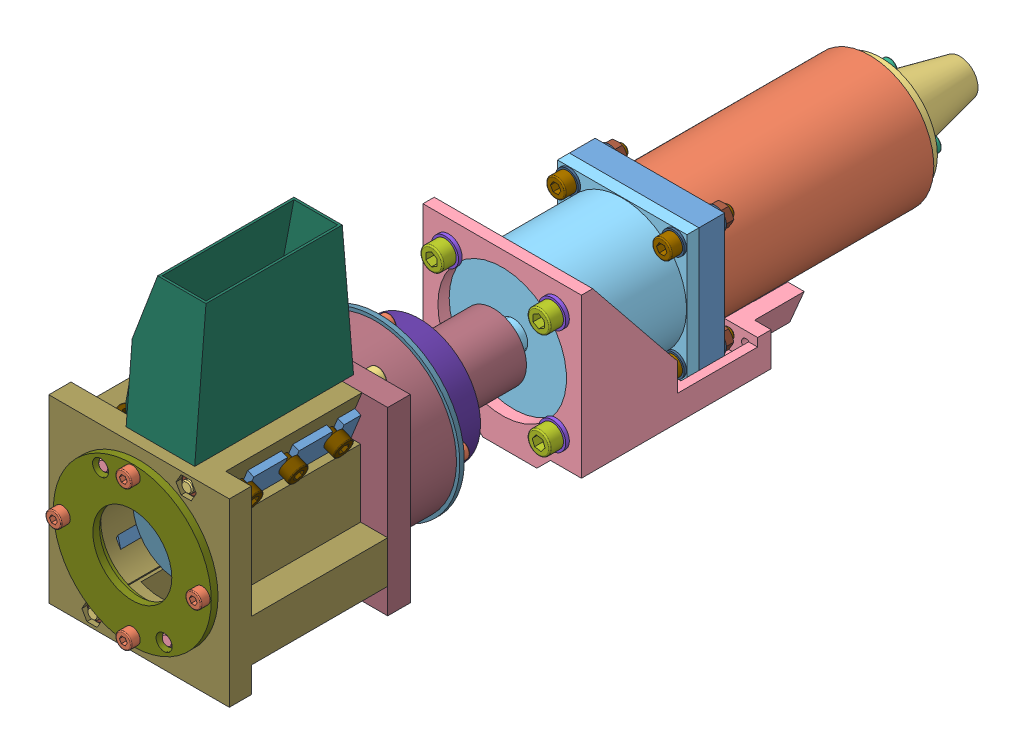
SolidWorks assembly 01_00_00-shredder_unit, configuration Standard. Lengths in mm.
Overall size (95.07 144 370.86).
107 component instances, 40 part files, 5 mates.
Components (placement in the parent):
- 01_01_00-powertrain_unit-1: 01_01_00-powertrain_unit [Standard] at (17.1226 7.6648 222.9) size (70.23 76.3 222.9)
  - 01_01_01-adapterplate_planetary_gear-1: 01_01_01-adapterplate_planetary_gear [Standard] at (50.4757 14.9234 40.5237) size (57.4 57.4 11.4)
  - 01_01_02-engine-1: 01_01_02-engine [Standard] at (50.4757 14.9234 -52.4763) size (56.8 56.8 93)
  - 01_01_03-engine_end_cap-1: 01_01_03-engine_end_cap [Standard] at (50.4757 14.9234 -52.4763) x (0 0 -1) z (1 0 0) size (40 50 50)
  - 01_01_04-engine_mount-1: 01_01_04-engine_mount [Standard] at (50.4757 14.9234 105.4237) x (-1 0 0) z (0 0 -1) size (70.23 76.3 106.1)
  - 01_01_05-planetary_gear-1: 01_01_05-planetary_gear [Standard] at (50.4757 14.9234 57.2237) size (57.4 57.4 78.5)
  - 01_01_06-cylinder_screw_M4x10-DIN912-1: 01_01_06-cylinder_screw_M4x10-DIN912 [Default] at (50.4757 34.3634 -57.4763) x (-0.923728 -0.383049 0) z (0 0 -1) size (7 7 14)
  - 01_01_06-cylinder_screw_M4x10-DIN912-2: 01_01_06-cylinder_screw_M4x10-DIN912 [Default] at (31.0357 14.9234 -57.4763) x (-0.923728 -0.383049 0) z (0 0 -1) size (7 7 14)
  - 01_01_06-cylinder_screw_M4x10-DIN912-3: 01_01_06-cylinder_screw_M4x10-DIN912 [Default] at (50.4757 -4.5166 -57.4763) x (-0.923728 -0.383049 0) z (0 0 -1) size (7 7 14)
  - 01_01_06-cylinder_screw_M4x10-DIN912-4: 01_01_06-cylinder_screw_M4x10-DIN912 [Default] at (69.9157 14.9234 -57.4763) x (-0.923728 -0.383049 0) z (0 0 -1) size (7 7 14)
  - 01_01_07-cylinder_screw_M6x16-DIN912-1: 01_01_07-cylinder_screw_M6x16-DIN912 [Default] at (74.2282 38.3194 112.0237) x (0.873403 -0.486997 0) z (0 0 1) size (10 10 22)
  - 01_01_07-cylinder_screw_M6x16-DIN912-2: 01_01_07-cylinder_screw_M6x16-DIN912 [Default] at (26.7231 38.3194 112.0237) x (0.863476 -0.50439 0) z (0 0 1) size (10 10 22)
  - 01_01_07-cylinder_screw_M6x16-DIN912-3: 01_01_07-cylinder_screw_M6x16-DIN912 [Default] at (26.7231 -8.4726 112.0237) x (0.985082 0.172086 0) z (0 0 1) size (10 10 22)
  - 01_01_07-cylinder_screw_M6x16-DIN912-4: 01_01_07-cylinder_screw_M6x16-DIN912 [Default] at (74.2282 -8.4726 112.0237) x (0.989059 -0.147523 0) z (0 0 1) size (10 10 22)
  - 01_01_08-washer_M6-ISO7089-1: 01_01_08-washer_M6-ISO7089 [Default] at (26.7231 38.3194 110.4237) size (12 12 1.6)
  - 01_01_08-washer_M6-ISO7089-2: 01_01_08-washer_M6-ISO7089 [Default] at (74.2282 38.3194 110.4237) size (12 12 1.6)
  - 01_01_08-washer_M6-ISO7089-3: 01_01_08-washer_M6-ISO7089 [Default] at (26.7231 -8.4726 112.0237) x (-0.923728 -0.383049 0) z (0 0 -1) size (12 12 1.6)
  - 01_01_08-washer_M6-ISO7089-4: 01_01_08-washer_M6-ISO7089 [Default] at (74.2282 -8.4726 110.4237) size (12 12 1.6)
  - 01_01_09-cylinder_screw_M5x25-DIN912-1: 01_01_09-cylinder_screw_M5x25-DIN912 [Default] at (73.9757 -8.5766 58.2237) size (8.5 8.5 30)
  - 01_01_09-cylinder_screw_M5x25-DIN912-2: 01_01_09-cylinder_screw_M5x25-DIN912 [Default] at (26.9757 -8.5766 58.2237) size (8.5 8.5 30)
  - 01_01_09-cylinder_screw_M5x25-DIN912-3: 01_01_09-cylinder_screw_M5x25-DIN912 [Default] at (73.9757 38.4234 58.2237) size (8.5 8.5 30)
  - 01_01_09-cylinder_screw_M5x25-DIN912-4: 01_01_09-cylinder_screw_M5x25-DIN912 [Default] at (26.9757 38.4234 58.2237) size (8.5 8.5 30)
  - 01_01_10-washer_M5-ISO7089-1: 01_01_10-washer_M5-ISO7089 [Default] at (73.9757 38.4234 57.2237) size (10 10 1)
  - 01_01_10-washer_M5-ISO7089-2: 01_01_10-washer_M5-ISO7089 [Default] at (26.9757 38.4234 57.2237) size (10 10 1)
  - 01_01_10-washer_M5-ISO7089-3: 01_01_10-washer_M5-ISO7089 [Default] at (73.9757 -8.5766 39.5237) size (10 10 1)
  - 01_01_10-washer_M5-ISO7089-4: 01_01_10-washer_M5-ISO7089 [Default] at (73.9757 38.4234 39.5237) size (10 10 1)
  - 01_01_10-washer_M5-ISO7089-5: 01_01_10-washer_M5-ISO7089 [Default] at (26.9757 -8.5766 57.2237) size (10 10 1)
  - 01_01_10-washer_M5-ISO7089-6: 01_01_10-washer_M5-ISO7089 [Default] at (73.9757 -8.5766 57.2237) size (10 10 1)
  - 01_01_10-washer_M5-ISO7089-7: 01_01_10-washer_M5-ISO7089 [Default] at (26.9757 38.4234 39.5237) size (10 10 1)
  - 01_01_10-washer_M5-ISO7089-8: 01_01_10-washer_M5-ISO7089 [Default] at (26.9757 -8.5766 39.5237) size (10 10 1)
  - 01_02_17-nut_M5-DIN934-1: 01_02_17-nut_M5-DIN934 [Default] at (26.9757 -8.5766 35.5237) size (9.24 8 4)
  - 01_02_17-nut_M5-DIN934-2: 01_02_17-nut_M5-DIN934 [Default] at (26.9757 38.4234 35.5237) size (9.24 8 4)
  - 01_02_17-nut_M5-DIN934-3: 01_02_17-nut_M5-DIN934 [Default] at (73.9757 -8.5766 35.5237) size (9.24 8 4)
  - 01_02_17-nut_M5-DIN934-4: 01_02_17-nut_M5-DIN934 [Default] at (73.9757 38.4234 35.5237) size (9.24 8 4)
- 01_02_00-cutting_unit-1: 01_02_00-cutting_unit [Standard] at (-26.7271 2.1966 389.5832) size (95.07 144 164.2)
  - 01_02_01-block-2: 01_02_01-block [Standard] at (54.3254 -19.6084 24.6959) size (81 88 109)
  - 01_02_02-counterplate-2: 01_02_02-counterplate [Standard] at (94.3254 20.3916 34.4959) x (0 1 0) z (0 0 -1) size (87.48 95.07 35)
  - 01_02_03-milling_Cutter-2: 01_02_03-milling_Cutter [Standard] at (94.3254 20.3916 87.4959) x (0 0 -1) z (0.834594 0.550866 0) size (115 40 40)
  - 01_02_04-hopper-3: 01_02_04-hopper [Standard] at (90.1822 35.5166 34.4959) size (35.4 73 70.4)
  - 01_02_05-deep_groove_ball_bearing_FAG6005_2Z-DIN625-1-3: 01_02_05-deep_groove_ball_bearing_FAG6005_2Z-DIN625-1 [Default] at (94.3254 20.3916 1.9959) x (0 0 1) z (0.97178 0.235887 0) size (12 47 47)
    - deep groove ball bearing _01-1: deep groove ball bearing _01 [Default] at origin size (12 32 32)
    - deep groove ball bearing _02-1: deep groove ball bearing _02 [Default] at origin size (12 47 47)
    - deep groove ball bearing _03-1: deep groove ball bearing _03 [Default] at origin size (8.55 8.62 8.66)
    - deep groove ball bearing _04-1: deep groove ball bearing _04 [Default] at origin size (8.18 8.8 8.53)
    - deep groove ball bearing _05-1: deep groove ball bearing _05 [Default] at origin size (8.18 8.8 8.53)
    - deep groove ball bearing _06-1: deep groove ball bearing _06 [Default] at origin size (8.18 8.8 8.53)
    - deep groove ball bearing _07-1: deep groove ball bearing _07 [Default] at origin size (8.6 8.66 8.93)
    - deep groove ball bearing _08-1: deep groove ball bearing _08 [Default] at origin size (8.6 8.66 8.93)
    - deep groove ball bearing _09-1: deep groove ball bearing _09 [Default] at origin size (8.51 7.97 8.51)
    - deep groove ball bearing _10-1: deep groove ball bearing _10 [Default] at origin size (8.51 7.97 8.51)
    - deep groove ball bearing _11-1: deep groove ball bearing _11 [Default] at origin size (8.51 7.97 8.51)
    - deep groove ball bearing _12-1: deep groove ball bearing _12 [Default] at origin size (7.71 8.16 8.45)
    - deep groove ball bearing _13-1: deep groove ball bearing _13 [Default] at origin size (1.7 43.25 43.25)
    - deep groove ball bearing _14-1: deep groove ball bearing _14 [Default] at origin size (1.7 43.25 43.25)
  - 01_02_05-deep_groove_ball_bearing_FAG6005_2Z-DIN625-1-4: 01_02_05-deep_groove_ball_bearing_FAG6005_2Z-DIN625-1 [Default] at (94.3254 20.3916 30.4959) x (0 0 -1) z (0.022494 -0.999747 0) size (12 47 47)
    - deep groove ball bearing _01-1: deep groove ball bearing _01 [Default] at origin size (12 32 32)
    - deep groove ball bearing _02-1: deep groove ball bearing _02 [Default] at origin size (12 47 47)
    - deep groove ball bearing _03-1: deep groove ball bearing _03 [Default] at origin size (8.55 8.62 8.66)
    - deep groove ball bearing _04-1: deep groove ball bearing _04 [Default] at origin size (8.18 8.8 8.53)
    - deep groove ball bearing _05-1: deep groove ball bearing _05 [Default] at origin size (8.18 8.8 8.53)
    - deep groove ball bearing _06-1: deep groove ball bearing _06 [Default] at origin size (8.18 8.8 8.53)
    - deep groove ball bearing _07-1: deep groove ball bearing _07 [Default] at origin size (8.6 8.66 8.93)
    - deep groove ball bearing _08-1: deep groove ball bearing _08 [Default] at origin size (8.6 8.66 8.93)
    - deep groove ball bearing _09-1: deep groove ball bearing _09 [Default] at origin size (8.51 7.97 8.51)
    - deep groove ball bearing _10-1: deep groove ball bearing _10 [Default] at origin size (8.51 7.97 8.51)
    - deep groove ball bearing _11-1: deep groove ball bearing _11 [Default] at origin size (8.51 7.97 8.51)
    - deep groove ball bearing _12-1: deep groove ball bearing _12 [Default] at origin size (7.71 8.16 8.45)
    - deep groove ball bearing _13-1: deep groove ball bearing _13 [Default] at origin size (1.7 43.25 43.25)
    - deep groove ball bearing _14-1: deep groove ball bearing _14 [Default] at origin size (1.7 43.25 43.25)
  - 01_02_06-bearing_Ring-1: 01_02_06-bearing_Ring [Standard] at (94.3254 20.3916 30.4959) x (0.18936 -0.981908 0) z (0 0 1) size (30 30 2)
  - 01_02_07-sleeve_milling_cutter_gear-2: 01_02_07-sleeve_milling_cutter_gear [Standard] at (94.3254 20.3916 -52.5041) size (29 29 50)
  - 01_02_08-bearing_sleeve_1-2: 01_02_08-bearing_sleeve_1 [Standard] at (94.3254 20.3916 -2.0041) x (0 0 1) z (-1 0 0) size (4 75 75)
  - 01_02_09-bearing_sleeve_2-2: 01_02_09-bearing_sleeve_2 [Standard] at (94.3254 20.3916 16.4959) x (0 0 1) z (-0.620419 -0.784271 0) size (4.5 32 32)
  - 01_02_10-shredder_end_cap-1: 01_02_10-shredder_end_cap [Standard] at (94.3254 20.3916 107.6959) x (-1 0 0) z (0 0 -1) size (70 70 6)
  - 01_02_11-clamping_flange-1: 01_02_11-clamping_flange [Standard] at (94.3254 20.3916 -19.6381) x (0.999731 0.023181 0) z (0 0 1) size (54 54 15)
  - 01_02_12-cylinder_screw_M5x10-DIN912-1: 01_02_12-cylinder_screw_M5x10-DIN912 [Default] at (68.0038 -5.8815 64.6959) x (0.927184 -0.374607 0) z (0 0 1) size (14.82 8.28 8.28)
  - 01_02_12-cylinder_screw_M5x10-DIN912-2: 01_02_12-cylinder_screw_M5x10-DIN912 [Default] at (68.0523 46.7131 44.6959) x (-0.374607 -0.927184 0) z (0 0 1) size (14.82 8.28 8.28)
  - 01_02_12-cylinder_screw_M5x10-DIN912-3: 01_02_12-cylinder_screw_M5x10-DIN912 [Default] at (68.0038 -5.8815 44.6959) x (0.927184 -0.374607 0) z (0 0 1) size (14.82 8.28 8.28)
  - 01_02_12-cylinder_screw_M5x10-DIN912-4: 01_02_12-cylinder_screw_M5x10-DIN912 [Default] at (68.0523 46.7131 64.6959) x (-0.374607 -0.927184 0) z (0 0 1) size (14.82 8.28 8.28)
  - 01_02_12-cylinder_screw_M5x10-DIN912-5: 01_02_12-cylinder_screw_M5x10-DIN912 [Default] at (68.0523 46.7131 84.6959) x (-0.374607 -0.927184 0) z (-0.577142 0.233181 0.782645) size (14.82 8.28 8.28)
  - 01_02_12-cylinder_screw_M5x10-DIN912-6: 01_02_12-cylinder_screw_M5x10-DIN912 [Default] at (68.0038 -5.8815 84.6959) x (0.927184 -0.374607 0) z (0 0 1) size (14.82 8.28 8.28)
  - 01_02_12-cylinder_screw_M5x10-DIN912-7: 01_02_12-cylinder_screw_M5x10-DIN912 [Default] at (120.647 46.6646 84.6959) x (-0.927184 0.374607 0) z (0 0 1) size (14.82 8.28 8.28)
  - 01_02_12-cylinder_screw_M5x10-DIN912-8: 01_02_12-cylinder_screw_M5x10-DIN912 [Default] at (120.647 46.6646 64.6959) x (-0.927184 0.374607 0) z (0 0 1) size (14.82 8.28 8.28)
  - 01_02_12-cylinder_screw_M5x10-DIN912-9: 01_02_12-cylinder_screw_M5x10-DIN912 [Default] at (120.647 46.6646 44.6959) x (-0.927184 0.374607 0) z (-0.253198 -0.626687 -0.73699) size (14.82 8.28 8.28)
  - 01_02_12-cylinder_screw_M5x10-DIN912-10: 01_02_12-cylinder_screw_M5x10-DIN912 [Default] at (120.5984 -5.93 84.6959) x (0.374607 0.927184 0) z (0 0 1) size (14.82 8.28 8.28)
  - 01_02_12-cylinder_screw_M5x10-DIN912-11: 01_02_12-cylinder_screw_M5x10-DIN912 [Default] at (120.5984 -5.93 64.6959) x (0.374607 0.927184 0) z (0 0 1) size (14.82 8.28 8.28)
  - 01_02_12-cylinder_screw_M5x10-DIN912-12: 01_02_12-cylinder_screw_M5x10-DIN912 [Default] at (120.5984 -5.93 44.6959) x (0.374607 0.927184 0) z (0 0 1) size (14.82 8.28 8.28)
  - 01_02_13-Cutter_head-1: 01_02_13-Cutter_head [Standard] at (113.3407 28.5809 34.6959) x (0.374607 0.927184 0) z (0 0 1) size (25 3 60)
  - 01_02_13-Cutter_head-2: 01_02_13-Cutter_head [Standard] at (102.5147 1.3763 34.6959) x (0.927184 -0.374607 0) z (0 0 1) size (25 3 60)
  - 01_02_13-Cutter_head-3: 01_02_13-Cutter_head [Standard] at (86.136 39.4069 35.0959) x (-0.927184 0.374607 0) z (0 0 1) size (25 3 60)
  - 01_02_13-Cutter_head-4: 01_02_13-Cutter_head [Standard] at (75.3101 12.2022 35.0959) x (-0.374607 -0.927184 0) z (0 0 1) size (25 3 60)
  - 01_02_14-cylinder_screw_M4x12-DIN912-1: 01_02_14-cylinder_screw_M4x12-DIN912 [Default] at (63.3254 20.3916 107.6959) size (7 7 16)
  - 01_02_14-cylinder_screw_M4x12-DIN912-2: 01_02_14-cylinder_screw_M4x12-DIN912 [Default] at (94.3254 -10.6084 107.6959) size (7 7 16)
  - 01_02_14-cylinder_screw_M4x12-DIN912-3: 01_02_14-cylinder_screw_M4x12-DIN912 [Default] at (94.3254 51.3916 107.6959) size (7 7 16)
  - 01_02_14-cylinder_screw_M4x12-DIN912-4: 01_02_14-cylinder_screw_M4x12-DIN912 [Default] at (125.3254 20.3916 107.6959) size (7 7 16)
  - 01_02_14-cylinder_screw_M4x12-DIN912-5: 01_02_14-cylinder_screw_M4x12-DIN912 [Default] at (126.8254 20.3916 -2.0041) x (-0.923728 -0.383049 0) z (0 0 -1) size (7 7 16)
  - 01_02_14-cylinder_screw_M4x12-DIN912-6: 01_02_14-cylinder_screw_M4x12-DIN912 [Default] at (94.3254 -12.1084 -2.0041) x (-0.923728 -0.383049 0) z (0 0 -1) size (7 7 16)
  - 01_02_14-cylinder_screw_M4x12-DIN912-7: 01_02_14-cylinder_screw_M4x12-DIN912 [Default] at (94.3254 52.8916 -2.0041) x (-0.923728 -0.383049 0) z (0 0 -1) size (7 7 16)
  - 01_02_14-cylinder_screw_M4x12-DIN912-8: 01_02_14-cylinder_screw_M4x12-DIN912 [Default] at (61.8254 20.3916 -2.0041) x (-0.923728 -0.383049 0) z (0 0 -1) size (7 7 16)
  - 01_02_15-cylinder_screw_M5x80-DIN912-1: 01_02_15-cylinder_screw_M5x80-DIN912 [Default] at (73.4663 -14.3237 24.4959) x (0 0 1) z (-1 0 0) size (84.82 8.28 8.28)
  - 01_02_15-cylinder_screw_M5x80-DIN912-2: 01_02_15-cylinder_screw_M5x80-DIN912 [Default] at (115.1844 55.1068 24.4959) x (0 0 1) z (-1 0 0) size (84.82 8.28 8.28)
  - 01_02_16-cylinder_screw_M5x100-DIN912-1: 01_02_16-cylinder_screw_M5x100-DIN912 [Default] at (80.2412 46.88 6.4959) x (0 0 1) z (-1 0 0) size (104.82 8.28 8.28)
  - 01_02_16-cylinder_screw_M5x100-DIN912-2: 01_02_16-cylinder_screw_M5x100-DIN912 [Default] at (108.4095 -6.0969 6.4959) x (0 0 1) z (-1 0 0) size (104.82 8.28 8.28)
  - 01_02_17-nut_M5-DIN934-1: 01_02_17-nut_M5-DIN934 [Default] at (73.4663 -14.3237 98.6959) x (0.499182 -0.866497 0) z (0 0 1) size (9.24 8 4)
  - 01_02_17-nut_M5-DIN934-2: 01_02_17-nut_M5-DIN934 [Default] at (108.4054 -6.0984 98.6959) x (0.819585 -0.572958 0) z (0 0 1) size (9.24 8 4)
  - 01_02_17-nut_M5-DIN934-3: 01_02_17-nut_M5-DIN934 [Default] at (80.2412 46.88 98.6959) x (0.233113 0.97245 0) z (0 0 1) size (9.24 8 4)
  - 01_02_17-nut_M5-DIN934-4: 01_02_17-nut_M5-DIN934 [Default] at (115.1844 55.1068 98.6959) x (0.773993 -0.633194 0) z (0 0 1) size (9.24 8 4)
Mates (geometry in assembly coordinates):
- Konzentrisch1: concentric aligned: cylinder of 01_01_00-powertrain_unit-1/01_01_05-planetary_gear-1 through (8.4397 9.1765 370.2) axis (0 0 -1) radius 6.33; cylinder of ? through (8.4397 9.1765 487.7) axis (0 0 -1) radius 12.5
- Abstand2: distance = 3 mm anti-aligned: plane of 01_01_00-powertrain_unit-1/01_01_05-planetary_gear-1 through (8.4397 9.1765 345.2) normal (0 0 1); plane of ? through (8.4397 9.1765 348.2) normal (0 0 -1)
- Konzentrisch2: concentric aligned: cylinder of 01_01_00-powertrain_unit-1/01_01_05-planetary_gear-1 through (67.5983 22.5881 353.3237) axis (0 0 -1) radius 6.33; cylinder of 01_02_00-cutting_unit-1/01_02_07-sleeve_milling_cutter_gear-2 through (67.5983 22.5881 337.0791) axis (0 0 -1) radius 6.25
- Deckungsgleich1: coincident aligned: plane of 01_01_00-powertrain_unit-1/01_01_05-planetary_gear-1 through (67.5983 22.5881 353.3237) normal (0 0 1); circle of 01_02_00-cutting_unit-1/01_02_07-sleeve_milling_cutter_gear-2
- Parallel1: parallel aligned: plane of 01_01_00-powertrain_unit-1/01_01_05-planetary_gear-1 through (38.8983 -6.1119 328.3237) normal (0 -1 0); plane of 01_02_00-cutting_unit-1/01_02_02-counterplate-2 through (27.5983 -17.4119 414.0791) normal (0 -1 0)
